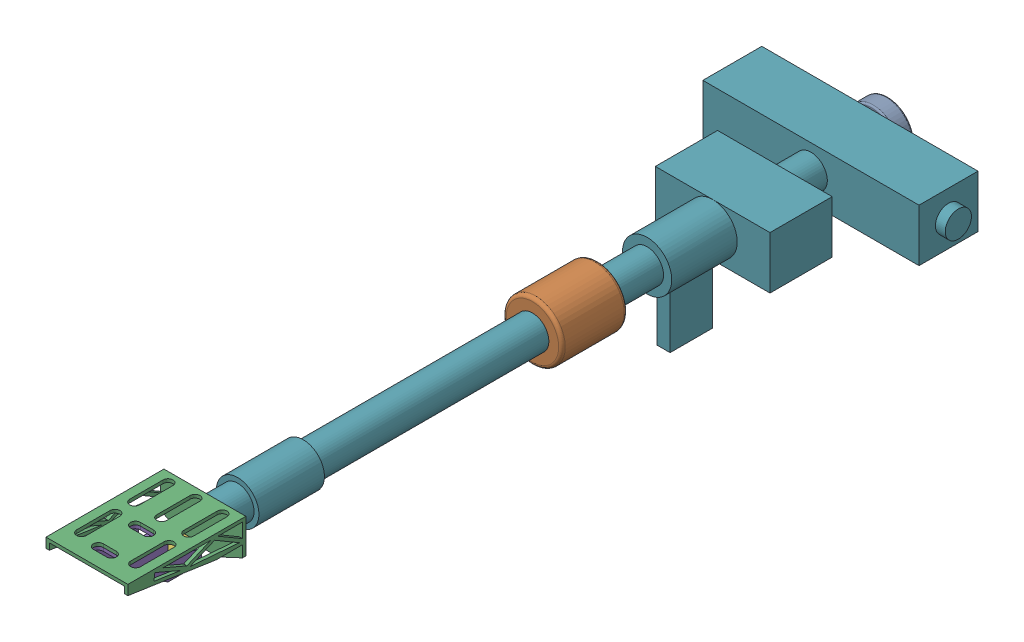
SolidWorks assembly Tone_arm, configuration Default. Lengths in mm.
Overall size (72 33.5 244.5).
8 component instances, 7 part files, 0 mates.
Components (placement in the parent):
- Weight-1: Weight [Default] at (789.4513 0.5 308.8386) x (0 0 -1) z (1 0 0) size (19.5 16 16)
- Tube_Weight-1: Tube_Weight [Default] at (0 0 -100) size (18 18 20)
- Bracket-1: Bracket [Default] at origin size (25 14 36)
- Element-1: Element [Default] at (194.418 86.2072 120.8597) x (1 0 0) z (0 1 0) size (10 27.52 13.64)
  - Needle-1: Needle [Default] at origin size (1.46 6.25 3.18)
  - House-1: House [Default] at (-194.418 123.0355 -85.6815) x (1 0 0) z (0 -1 0) size (10 12 27.52)
  - Connector-1: Connector [Default] at (-194.418 120.8597 -86.2072) x (1 0 0) z (0 -1 0) size (6 5 7.93)
- Arm-1: Arm [Default] at (-242 0 0) size (72 32 203)
